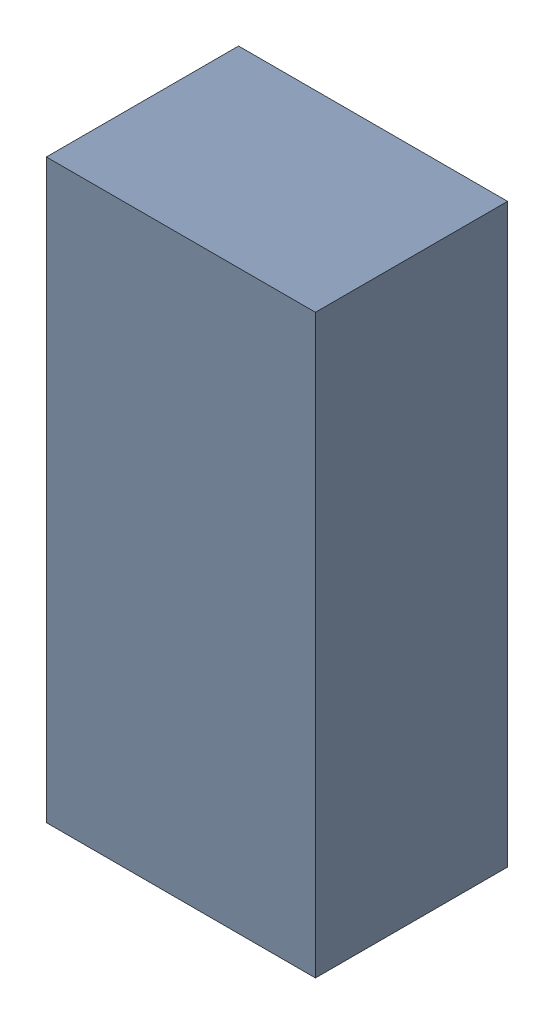
SolidWorks assembly Q2, configuration Default. Lengths in mm.
Overall size (1.4 3 1).
2 component instances, 1 part files, 0 mates.
Components (placement in the parent):
- 959206624-1: 959206624 [Default] at (158.496 90.17 0.1) size (1.4 3 1)
  - Extruded-10-1: Extruded-10 [Default] at origin size (1.4 3 1)
